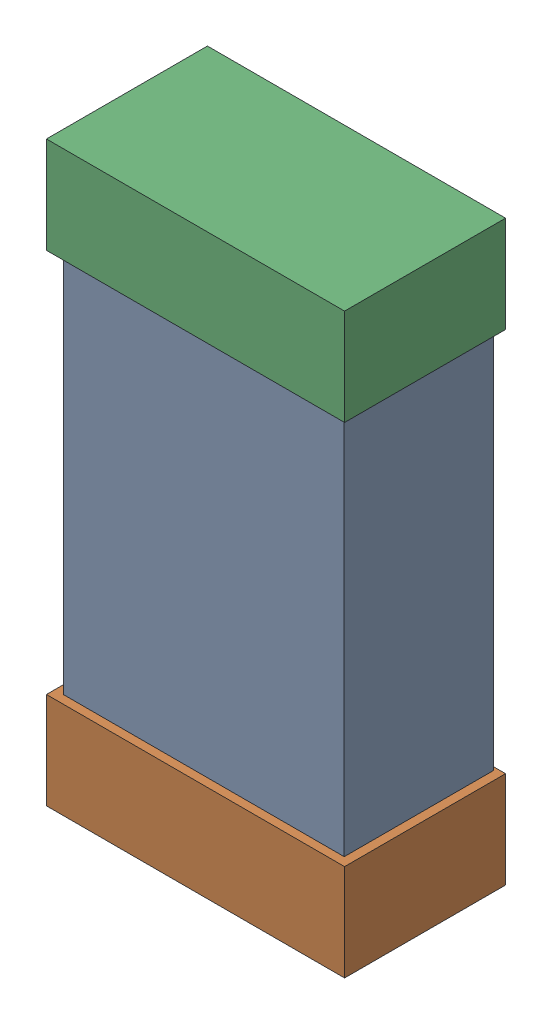
SolidWorks assembly PWR2, configuration Default. Lengths in mm.
Overall size (0.85 1.65 0.46).
6 component instances, 2 part files, 0 mates.
Components (placement in the parent):
- 432124816_41-1: 432124816_41 [Default] at (41.5501 41.0501 -0.8615) size (0.8 1.5 0.42)
  - Extruded (1)-1: Extruded (1) [Default] at origin size (0.8 1.5 0.42)
- 432138512_82-1: 432138512_82 [Default] at (41.5501 40.3643 -0.8715) size (0.85 0.28 0.46)
  - Extruded-1: Extruded [Default] at origin size (0.85 0.28 0.46)
- 432138512_83-1: 432138512_83 [Default] at (41.5501 41.7358 -0.8715) size (0.85 0.28 0.46)
  - Extruded-1: Extruded [Default] at origin size (0.85 0.28 0.46)
